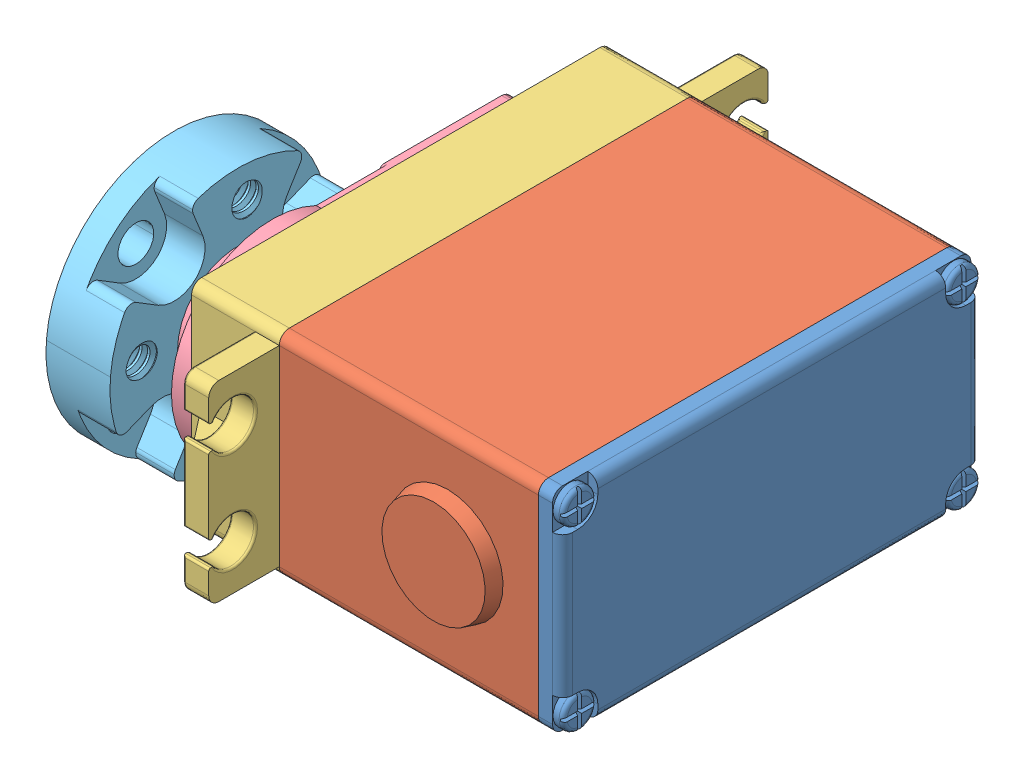
SolidWorks assembly MS-SA-0012j Torpedo Servo Assembly, configuration Default. Lengths in mm.
Overall size (48.58 27.42 55.5).
7 component instances, 6 part files, 9 mates.
Components (placement in the parent):
- Hitec HS-646WP-1: Hitec HS-646WP [Default] at (71.9223 31.717 49.4945) x (0 1 0) z (0 0 1) size (21 45.43 55.5)
  - 11886_bottom-1: 11886_bottom [Default] at (2.2223 -4.2785 0.9275) size (21 2.43 41.5)
  - 11886_middle-1: 11886_middle [Default] at (2.2223 -1.8785 0.9275) size (21 25.7 42.9)
  - 11886_upper-1: 11886_upper [Default] at (6.1473 23.8215 -5.3225) size (21 8.72 55.5)
  - 11886_top-1: 11886_top [Default] at (2.2223 32.5215 0.7275) size (20 8.6 36.5)
- MS-C-0027-Servo Horn-1: MS-C-0027-Servo Horn [Default] at (34.0008 33.9393 61.172) x (0 -0.996508 0.083501) z (0 -0.083501 -0.996508) size (25.39 6.35 25.39)
- MS-P-0110 Servo Holder-1: MS-P-0110 Servo Holder [Default] at (40.4008 -0.2 100.4441) x (0 0 -1) z (1 0 0) size (58.32 25.24 10) (hidden)
Mates (geometry in assembly coordinates):
- Concentric1: concentric aligned: circle of MS-P-0055-03 Hand Servo Mount-1; circle of 11886-1/11886_upper-1
- Coincident1: coincident anti-aligned: plane of MS-P-0055-03 Hand Servo Mount-1 through (45.6008 33.9393 61.1705) normal (1 0 0); plane of 11886-1/11886_upper-1 through (45.6008 16.8334 22.672) normal (-1 0 0)
- Parallel1: parallel aligned: plane of MS-P-0055-03 Hand Servo Mount-1 through (-71.2981 47.9093 61.1705) normal (0 1 0); plane of 11886-1/11886_middle-1 through (48.1008 44.4393 71.172) normal (0 1 0)
- Concentric6: concentric anti-aligned: circle of 11886-1/11886_top-1; circle of MS-C-0027-Servo Horn-1
- Coincident3: coincident anti-aligned: plane of 11886-1/11886_top-1 through (34.0008 33.9393 61.172) normal (-1 0 0); plane of MS-C-0027-Servo Horn-1 through (34.0008 33.9393 61.172) normal (1 0 0)
- Concentric7: concentric aligned: circle of MS-C-0027-Servo Horn-1; circle of MS-P-0060-03-Hand Servo Pulley-1
- Concentric8: concentric aligned: circle of MS-C-0027-Servo Horn-1; circle of MS-P-0060-03-Hand Servo Pulley-1
- Coincident4: coincident anti-aligned: plane of MS-C-0027-Servo Horn-1 through (27.6508 33.9393 61.172) normal (-1 0 0); plane of MS-P-0060-03-Hand Servo Pulley-1 through (27.6508 33.9393 61.172) normal (1 0 0)
- Coincident10: coincident aligned: plane of 11886-1/11886_top-1 through (35.4008 33.9393 61.172) normal (-1 0 0); plane of Servo holder-1 through (35.4008 -0.2 100.4441) normal (-1 0 0)
